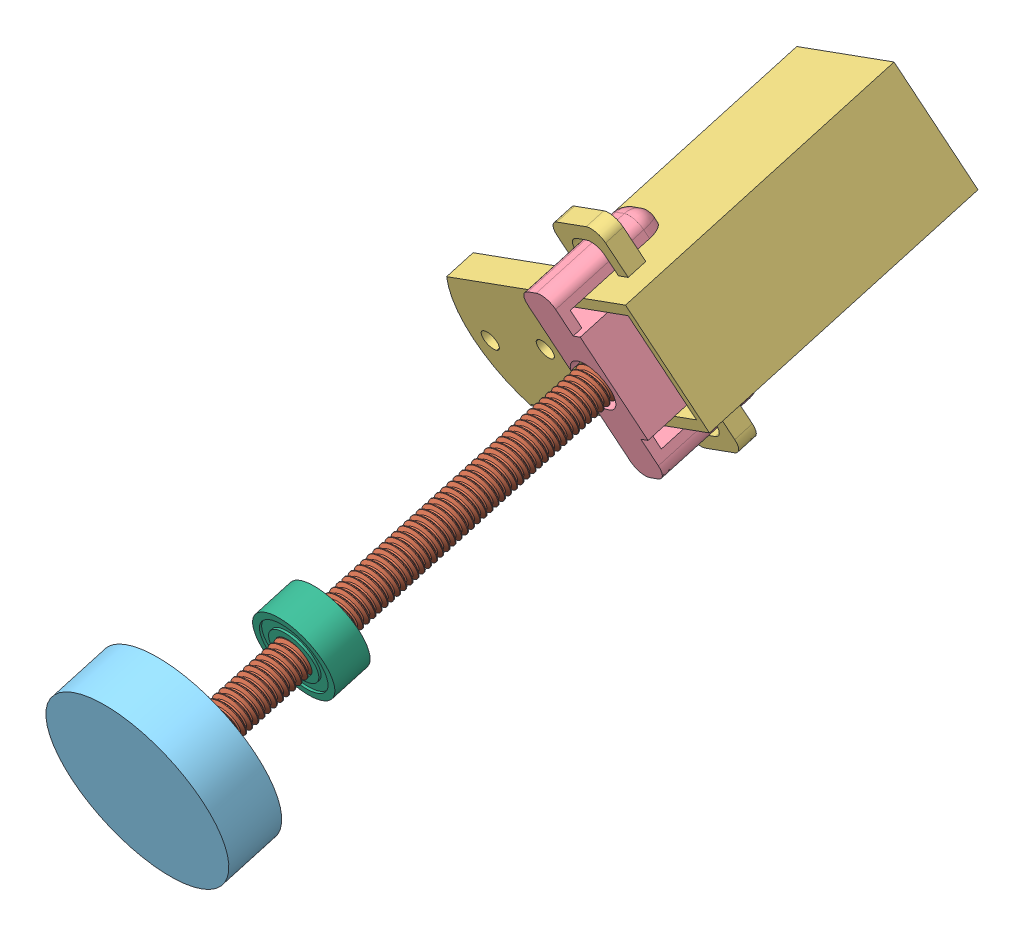
SolidWorks assembly Motor& Roller Assembly, configuration Default. Lengths in mm.
Overall size (38.09 49.96 91.68).
6 component instances, 6 part files, 8 mates.
Components (placement in the parent):
- M4 Nut-1: M4 Nut [Default] at (-57.6078 23.6231 20.5659) x (-0.029593 -0.308146 0.950879) z (-0.746697 -0.625603 -0.225974) size (3.68 8.08 7)
- New Motor-1: New Motor [Default] at (-55.0798 47.2645 -54.1441) x (0.888476 0.427744 0.166268) z (-0.029593 -0.308146 0.950879) size (12 10.57 80.84)
- New Motor case2-1: New Motor case2 [Default] at (-61.0264 35.7877 -27.0245) x (0.457967 -0.849754 -0.261122) z (0.029593 0.308146 -0.950879) size (23 30 30.5)
- New Motor enclosure-1: New Motor enclosure [Default] at (-56.0797 37.2316 -23.2476) x (0.457967 -0.849754 -0.261122) z (0.029593 0.308146 -0.950879) size (18.9 5.4 12)
- New Motor roller-1: New Motor roller [Default] at (-57.4381 24.395 18.2973) x (0.972856 0.20955 0.098185) z (-0.029593 -0.308146 0.950879) size (20 20 8)
- Bearing-1: Bearing [Default] at (-57.0267 27.371 7.1805) x (0.911456 -0.398837 -0.100882) z (0.410332 0.863699 0.292664) size (9 4 9)
Mates (geometry in assembly coordinates):
- Coincident9: coincident anti-aligned: plane of New Motor-1 through (-55.8196 39.5608 -30.3722) normal (-0.029593 -0.308146 0.950879); plane of New Motor enclosure-1 through (-55.8577 39.5427 -30.3792) normal (0.029593 0.308146 -0.950879)
- Parallel4: parallel anti-aligned: plane of New Motor-1 through (-52.7786 46.3761 -28.0689) normal (-0.457967 0.849754 0.261122); plane of New Motor enclosure-1 through (-53.4534 35.0815 -31.7501) normal (0.457967 -0.849754 -0.261122)
- Coincident10: coincident anti-aligned: plane of New Motor-1 through (-55.0798 47.2645 -54.1441) normal (0.029593 0.308146 -0.950879); plane of New Motor case2-1 through (-60.1534 44.878 -55.0754) normal (-0.029593 -0.308146 0.950879)
- Coincident11: coincident anti-aligned: plane of M4 Nut-1 through (-57.6551 23.13 22.0873) normal (-0.029593 -0.308146 0.950879); plane of New Motor roller-1 through (-57.5565 23.1624 22.1009) normal (0.029593 0.308146 -0.950879)
- Parallel5: parallel anti-aligned: plane of M4 Nut-1 through (-60.3407 26.0266 22.9424) normal (-0.948827 0.307884 0.070245); plane of New Motor roller-1 through (-60.298 26.7993 21.0908) normal (0.948827 -0.307884 -0.070245)
- Coincident12: coincident anti-aligned: plane of New Motor-1 through (-57.4473 22.6128 21.9262) normal (-0.029593 -0.308146 0.950879); plane of New Motor roller-1 through (-57.5565 23.1624 22.1009) normal (0.029593 0.308146 -0.950879)
- Concentric1: concentric anti-aligned: circle of New Motor enclosure-1; cylinder of Bearing-1 through (-57.0267 27.371 7.1805) axis (-0.029593 -0.308146 0.950879) radius 2
- Distance1: distance = 33 mm anti-aligned: plane of New Motor case2-1 through (-66.9778 32.7878 -28.1819) normal (-0.029593 -0.308146 0.950879); plane of Bearing-1 through (-53.5495 26.4916 4.9004) normal (0.029593 0.308146 -0.950879)
